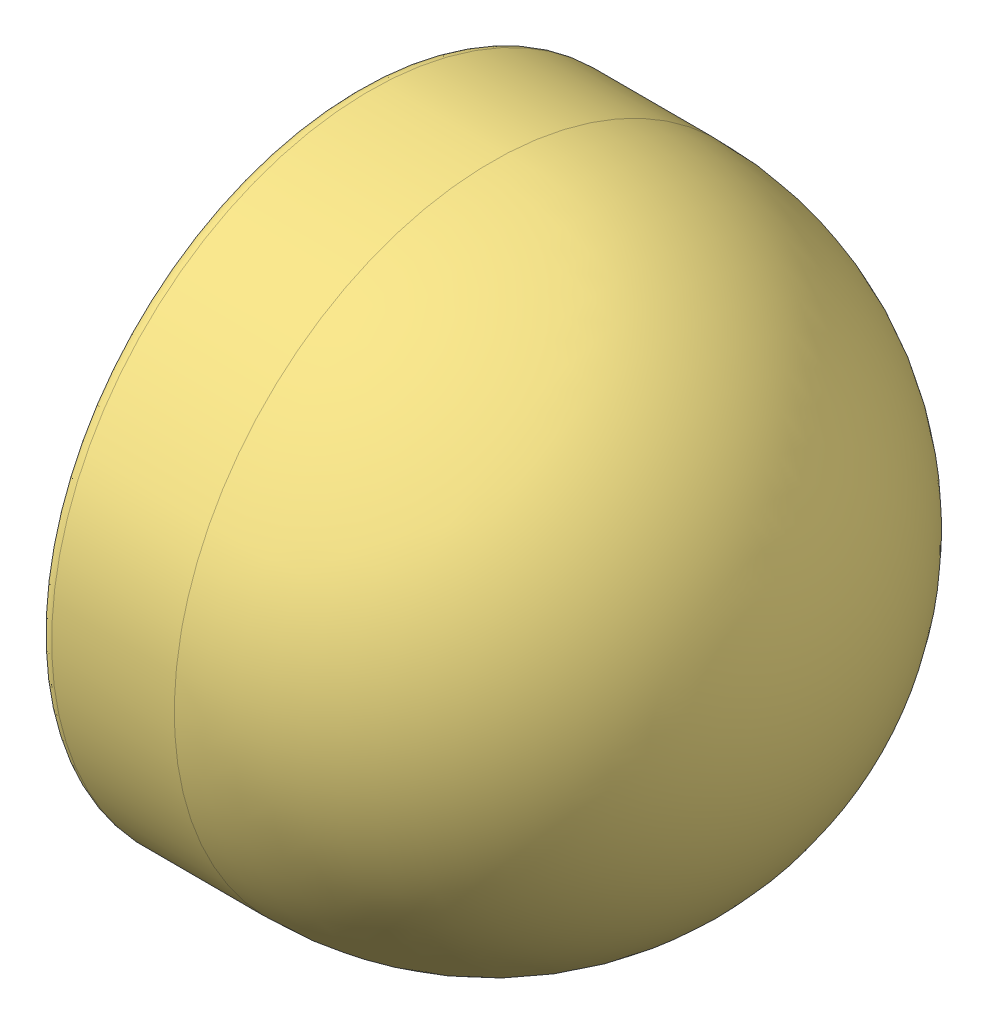
SolidWorks assembly Assem1, configuration Default. Lengths in mm.
Overall size (120.85 167.94 167.94).
4 component instances, 4 part files, 6 mates.
Components (placement in the parent):
- 6.Front Light Bulb-1: 6.Front Light Bulb [Default] at (-76.9745 32.3368 62.3068) x (1 0 0) z (0 -0.58962 -0.807681) size (25.36 19 19)
- 8.Bulb cover-1: 8.Bulb cover [Default] at (-146.4674 32.3368 62.3068) size (29.99 128 128)
- 7.Front Light Case-1: 7.Front Light Case [Default] at (-13.4674 32.3368 62.3068) x (1 0 0) z (0 0.225273 0.974296) size (100 140 140)
- 9.Front Light Glass-1: 9.Front Light Glass [Default] at (-84.4674 32.3368 62.3068) x (1 0 0) z (0 0.926957 0.375168) size (33.85 128 128)
Mates (geometry in assembly coordinates):
- Concentric1: concentric aligned: cylinder of 6.Front Light Bulb-1 through (-78.9745 32.3368 62.3068) axis (-1 0 0) radius 5; cylinder of 8.Bulb cover-1 through (-146.4674 32.3368 62.3068) axis (-1 0 0) radius 5
- Coincident1: coincident anti-aligned: plane of 6.Front Light Bulb-1 through (-76.4745 28.2984 65.2549) normal (1 0 0); plane of 8.Bulb cover-1 through (-76.4745 49.2183 62.3068) normal (-1 0 0)
- Concentric3: concentric anti-aligned: cylinder of 8.Bulb cover-1 through (-146.4674 32.3368 62.3068) axis (-1 0 0) radius 64; cylinder of 9.Front Light Glass-1 through (-84.4674 32.3368 62.3068) axis (1 0 0) radius 64
- Coincident6: coincident anti-aligned: plane of 8.Bulb cover-1 through (-100.4674 95.3368 62.3068) normal (-1 0 0); plane of 9.Front Light Glass-1 through (-100.4674 56.3475 2.9816) normal (1 0 0)
- Concentric4: concentric: cylinder of 8.Bulb cover-1 through (-146.4674 32.3368 62.3068) axis (-1 0 0) radius 64; cylinder of 7.Front Light Case-1 through (38.1518 32.3368 62.3068) axis (-1 0 0) radius 70
- Coincident9: coincident aligned: circle of 8.Bulb cover-1; circle of 7.Front Light Case-1
